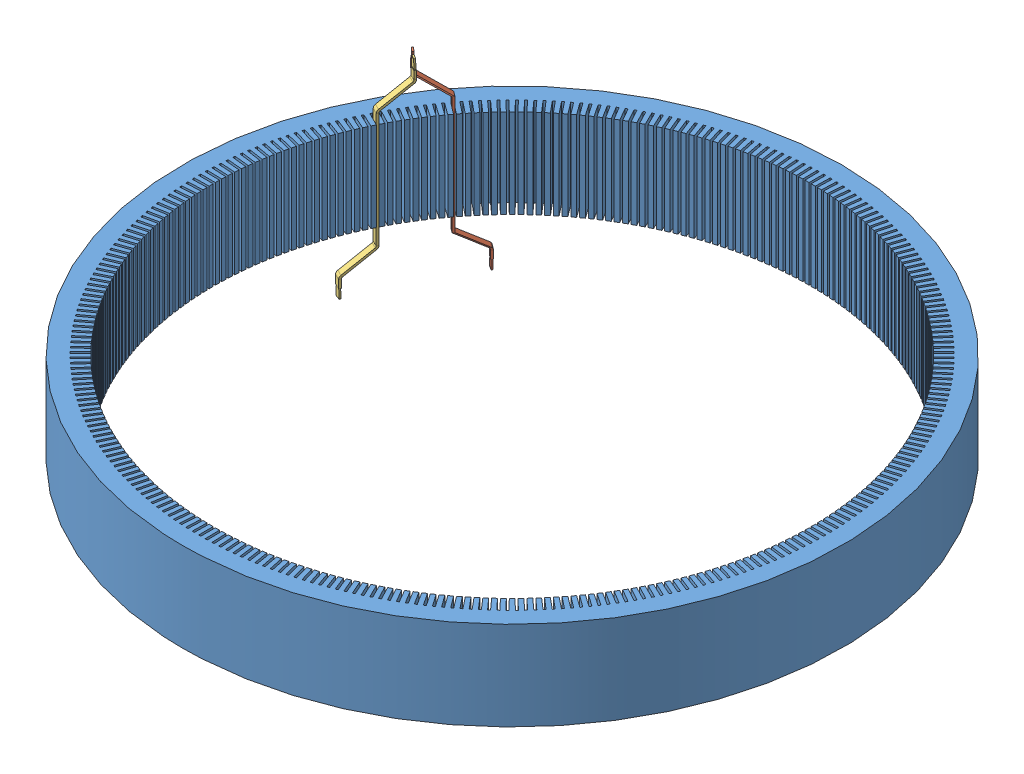
SolidWorks assembly Assem2, configuration Default. Lengths in mm.
Overall size (6858 2044.59 6858).
3 component instances, 3 part files, 9 mates.
Components (placement in the parent):
- laminasyon35mm_Ns300_Slot22_2022_11_17-1: laminasyon35mm_Ns300_Slot22_2022_11_17 [Default] at (1947.3861 2828.6707 5782.7862) size (6858 925 6858)
- Symmetric_Bottom-1: Symmetric_Bottom [Default] at (-613.9797 2628.6705 3838.6037) x (0.79653 0 0.604599) z (-0.604599 0 0.79653) size (115.46 2023.92 605.71)
- Symmetric_Top-1: Symmetric_Top [Default] at (-993.1307 2339.7884 4649.1601) x (0.895712 0 0.444635) z (-0.444635 0 0.895712) size (70.25 2034 605.71)
Mates (geometry in assembly coordinates):
- Coincident2: coincident anti-aligned: plane of laminasyon35mm_Ns300_Slot22_2022_11_17-1 through (-641.9578 3753.6707 3817.3672) normal (0.79653 0 0.604599); plane of Symmetric_Bottom-1 through (-635.4281 2628.6705 3808.7646) normal (-0.79653 0 -0.604599)
- Parallel2: parallel anti-aligned: plane of laminasyon35mm_Ns300_Slot22_2022_11_17-1 through (1940.7355 3753.6707 5791.548) normal (0.604599 0 -0.79653); plane of Symmetric_Bottom-1 through (-648.4875 2628.6705 3825.9697) normal (-0.604599 0 0.79653)
- Distance1: distance = 0.2 mm anti-aligned: plane of laminasyon35mm_Ns300_Slot22_2022_11_17-1 through (1940.7355 3753.6707 5791.548) normal (0.604599 0 -0.79653); plane of Symmetric_Bottom-1 through (-648.4875 2628.6705 3825.9697) normal (-0.604599 0 0.79653)
- Distance2: distance = 100 mm: line of Symmetric_Bottom-1 through (-648.4875 3853.6705 3825.9697) axis (0.79653 0 0.604599); line of laminasyon35mm_Ns300_Slot22_2022_11_17-1 through (-527.5358 3753.6707 3918.0281) axis (-0.79653 0 -0.604599)
- Parallel4: parallel anti-aligned: plane of laminasyon35mm_Ns300_Slot22_2022_11_17-1 through (-964.3762 3753.6707 4337.3748) normal (0.895712 0 0.444635); plane of Symmetric_Top-1 through (-889.9325 2659.9045 4362.2715) normal (-0.895712 0 -0.444635)
- Parallel5: parallel anti-aligned: plane of laminasyon35mm_Ns300_Slot22_2022_11_17-1 through (1952.2771 3753.6707 5772.9333) normal (-0.444635 0 0.895712); plane of Symmetric_Top-1 through (-889.9325 2659.9045 4362.2715) normal (0.444635 0 -0.895712)
- Distance3: distance = 0.2 mm anti-aligned: plane of Symmetric_Top-1 through (-889.9325 2659.9045 4362.2715) normal (0.444635 0 -0.895712); plane of laminasyon35mm_Ns300_Slot22_2022_11_17-1 through (1952.2771 3753.6707 5772.9333) normal (-0.444635 0 0.895712)
- Distance4: distance = 77.75 mm anti-aligned: plane of Symmetric_Top-1 through (-889.9325 2659.9045 4362.2715) normal (-0.895712 0 -0.444635); plane of laminasyon35mm_Ns300_Slot22_2022_11_17-1 through (-964.3762 3753.6707 4337.3748) normal (0.895712 0 0.444635)
- Distance5: distance = 100 mm: point of Symmetric_Top-1; line of laminasyon35mm_Ns300_Slot22_2022_11_17-1 through (-959.4852 3753.6707 4327.522) axis (0.895712 0 0.444635)
